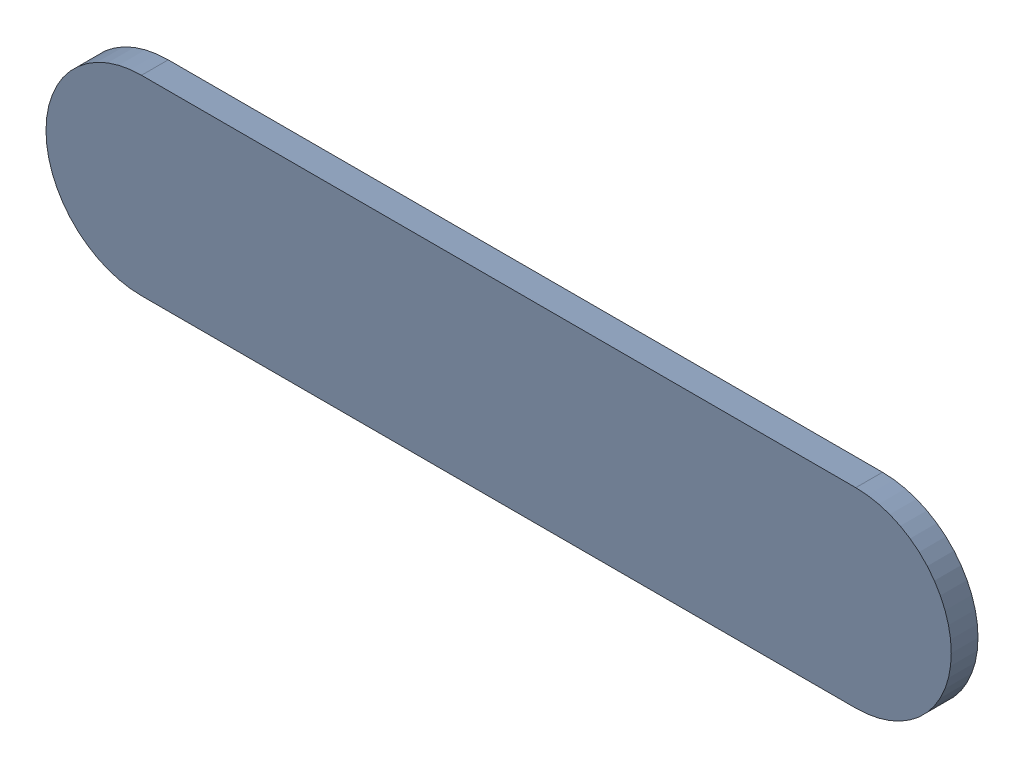
SolidWorks assembly Track (29mm,40mm)(29.95mm,40mm) on Top Layer, configuration Predeterminado. Lengths in mm.
Overall size (1.2 0.25 0.04).
2 component instances, 1 part files, 0 mates.
Components (placement in the parent):
- Track (29mm,40mm)(29.95mm,40mm) on Top Layer-1-1: Track (29mm,40mm)(29.95mm,40mm) on Top Layer-1 [Predeterminado] at (-68.317 -44.187 -0.0457) size (1.2 0.25 0.04)
  - Track (29mm,40mm)(29.95mm,40mm) on Top Layer-Part-1-1: Track (29mm,40mm)(29.95mm,40mm) on Top Layer-Part-1 [Predeterminado] at origin size (1.2 0.25 0.04)
